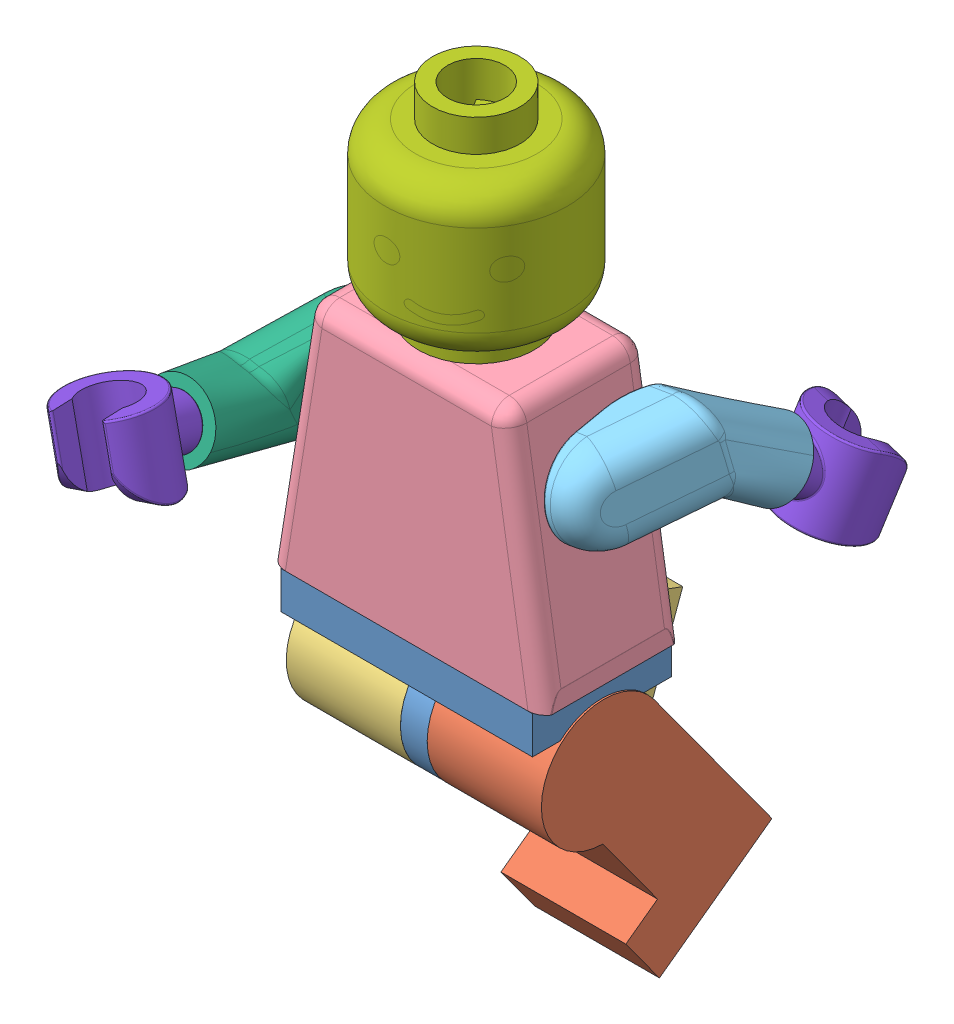
SolidWorks assembly Practice Model -  Lego, configuration Default. Lengths in mm.
Overall size (24.46 41.49 29.35).
11 component instances, 8 part files, 9 mates.
Components (placement in the parent):
- Practice Model - Lego Legs & hips-1: Practice Model - Lego Legs & hips [Default] at origin size (14.3 21.09 17.26) (flexible)
  - Practice Model -Lego Hips in progress.-1: Practice Model -Lego Hips in progress. [Default] at origin size (14.1 13 7.8)
  - Practice Model - Lego Leg (Left)-1: Practice Model - Lego Leg (Left) [Default] at (7.15 -4.7 0) x (1 0 0) z (0 -0.588499 0.808498) size (7 14.7 7.8)
  - MirrorPractice Model - Lego Leg (Left)-2: MirrorPractice Model - Lego Leg (Left) [Default] at (-7.15 -4.7 0) x (-1 0 0) z (0 0.939693 -0.34202) size (7 14.7 7.8)
- Practice Model - Lego in Progress-1: Practice Model - Lego in Progress [Default] at origin size (22.68 19.3 19.96) (flexible)
  - Practice Model - Lego Torso in progress-1: Practice Model - Lego Torso in progress [Default] at origin size (15.31 19.3 7.8)
  - Practice Model - Lego arm in progress-1: Practice Model - Lego arm in progress [Default] at (8.3031 9.5692 -1.9192) x (0.987417 0.158141 0) z (0.155639 -0.971797 -0.177166) size (7.07 11.6 7.6)
  - MirrorPractice Model - Lego arm in progress1-4: MirrorPractice Model - Lego arm in progress1 [Default] at (-8.5044 8.3125 1.7154) x (-0.987417 0.158141 0) z (-0.139118 -0.868638 -0.475514) size (7.07 11.6 7.6)
- Practice Model - Lego Head1-1: Practice Model - Lego Head1 [Default] at (0 13.8 0) x (0.867863 0 -0.496804) z (0.496804 0 0.867863) size (10.2 11.4 10.2)
- Practice Model - Lego Hand (R)-1: Practice Model - Lego Hand (R) [Default] at (-7.6156 7.1958 12.0292) x (0.962075 0.246023 -0.117829) z (0.10385 0.069089 0.99219) size (5.15 4.95 11.43)
- Practice Model - Lego Hand (R)-2: Practice Model - Lego Hand (R) [Default] at (9.4074 7.5033 -12.0811) x (0.981133 -0.091263 0.170439) z (0.125983 -0.366907 -0.921687) size (5.15 4.95 11.43)
Mates (geometry in assembly coordinates):
- Coincident1: coincident anti-aligned: plane of Practice Model - Lego Legs & hips-1/Practice Model -Lego Hips in progress.-1 through (7.05 0 0) normal (0 1 0); plane of Practice Model - Lego in Progress-1/Practice Model - Lego Torso in progress-1 through (7.65 0 3.9) normal (0 -1 0)
- Width1: width aligned: plane of Practice Model - Lego Legs & hips-1/Practice Model -Lego Hips in progress.-1 through (7.05 0 0) normal (1 0 0); plane of Practice Model - Lego in Progress-1/Practice Model - Lego Torso in progress-1 through (-7.05 0 0) normal (-1 0 0); plane of Practice Model - Lego Legs & hips-1/Practice Model -Lego Hips in progress.-1 through (-7.65 1 3.9) normal (-0.987417 0.158141 0); plane of Practice Model - Lego in Progress-1/Practice Model - Lego Torso in progress-1 through (7.65 1 3.9) normal (0.987417 0.158141 0)
- Width2: width anti-aligned: plane of Practice Model - Lego Legs & hips-1/Practice Model -Lego Hips in progress.-1 through (7.05 0 -3.9) normal (0 0 -1); plane of Practice Model - Lego in Progress-1/Practice Model - Lego Torso in progress-1 through (7.05 0 3.9) normal (0 0 1); plane of Practice Model - Lego Legs & hips-1/Practice Model -Lego Hips in progress.-1 through (0 0 3.9) normal (0 0 1); plane of Practice Model - Lego in Progress-1/Practice Model - Lego Torso in progress-1 through (0 0 -3.9) normal (0 0 -1)
- Concentric2: concentric anti-aligned: cylinder of Practice Model - Lego in Progress-1/Practice Model - Lego Torso in progress-1 through (0 19.3 0) axis (0 -1 0) radius 2.4; cylinder of Practice Model - Lego Head1-1 through (0 30.1137 0) axis (0 1 0) radius 2.45
- Coincident5: coincident anti-aligned: plane of Practice Model - Lego in Progress-1/Practice Model - Lego Torso in progress-1 through (-5.6 13.8 3.9) normal (0 1 0); plane of Practice Model - Lego Head1-1 through (-1.6146 13.8 -2.8206) normal (0 -1 0)
- Concentric3: concentric anti-aligned: cylinder of Practice Model - Lego in Progress-1/MirrorPractice Model - Lego arm in progress1-4 through (-8.7053 7.0577 2.843) axis (0.045198 0.282212 0.958287) radius 1.125; cylinder of Practice Model - Lego Hand (R)-1 through (-8.1645 10.4342 14.3082) axis (-0.045198 -0.282212 -0.958287) radius 1.125
- Coincident6: coincident anti-aligned: plane of Practice Model - Lego in Progress-1/MirrorPractice Model - Lego arm in progress1-4 through (-8.4477 8.666 8.3053) normal (0.045198 0.282212 0.958287); circle of Practice Model - Lego Hand (R)-1
- Concentric4: concentric anti-aligned: cylinder of Practice Model - Lego in Progress-1/Practice Model - Lego arm in progress-1 through (8.1678 10.4137 -3.387) axis (0.090242 -0.563465 -0.821196) radius 1.125; cylinder of Practice Model - Lego Hand (R)-2 through (9.2475 3.6723 -13.212) axis (-0.090242 0.563465 0.821196) radius 1.125
- Coincident7: coincident aligned: plane of Practice Model - Lego in Progress-1/Practice Model - Lego arm in progress-1 through (8.6822 7.2023 -8.0681) normal (0.090242 -0.563465 -0.821196); circle of Practice Model - Lego Hand (R)-2
